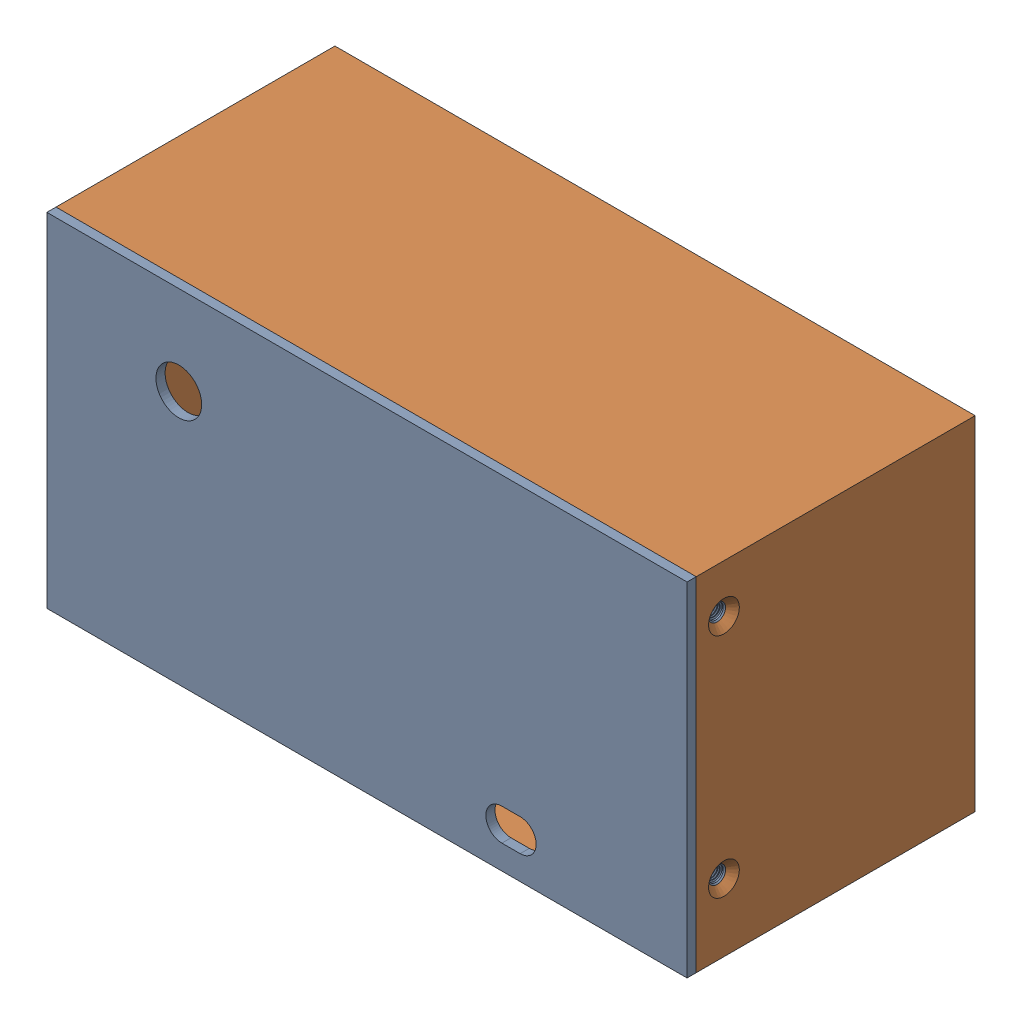
SolidWorks assembly FreLight, configuration 默认. Lengths in mm.
Overall size (140 75 63).
3 component instances, 3 part files, 5 mates.
Components (placement in the parent):
- 后盖-1: 后盖 [默认] at (-88.5821 -0.2776 3.5) size (140 75 12)
- 外壳-1: 外壳 [默认] at (-82.6673 8.7466 -57.5) size (140 75 61)
- 栅格-1: 栅格 [默认] at (-63.2691 2.8845 -50.7) x (1 0 0) z (0 1 0) size (131.9 3 65.9)
Mates (geometry in assembly coordinates):
- 重合26: coincident anti-aligned: plane of 外壳-1 through (2.6809 39.3345 -51) normal (-1 0 0); plane of 栅格-1 through (2.6809 -30.0655 -53.7) normal (1 0 0)
- 重合28: coincident anti-aligned: plane of 外壳-1 through (-131.9191 -30.0655 -51) normal (0 1 0); plane of 栅格-1 through (-129.2191 -30.0655 -53.7) normal (0 -1 0)
- 重合34: coincident anti-aligned: plane of 后盖-1 through (5.0809 39.3345 -6.5) normal (1 0 0); plane of 外壳-1 through (5.0809 40.8345 3.5) normal (-1 0 0)
- 重合35: coincident anti-aligned: plane of 后盖-1 through (-120.4191 -32.6655 -6.5) normal (0 -1 0); plane of 外壳-1 through (-133.4191 -32.6655 3.5) normal (0 1 0)
- 重合36: coincident aligned: line of 后盖-1 through (-133.4191 40.8345 3.5) axis (0 -1 0); line of 外壳-1 through (-133.4191 40.8345 3.5) axis (0 -1 0)
